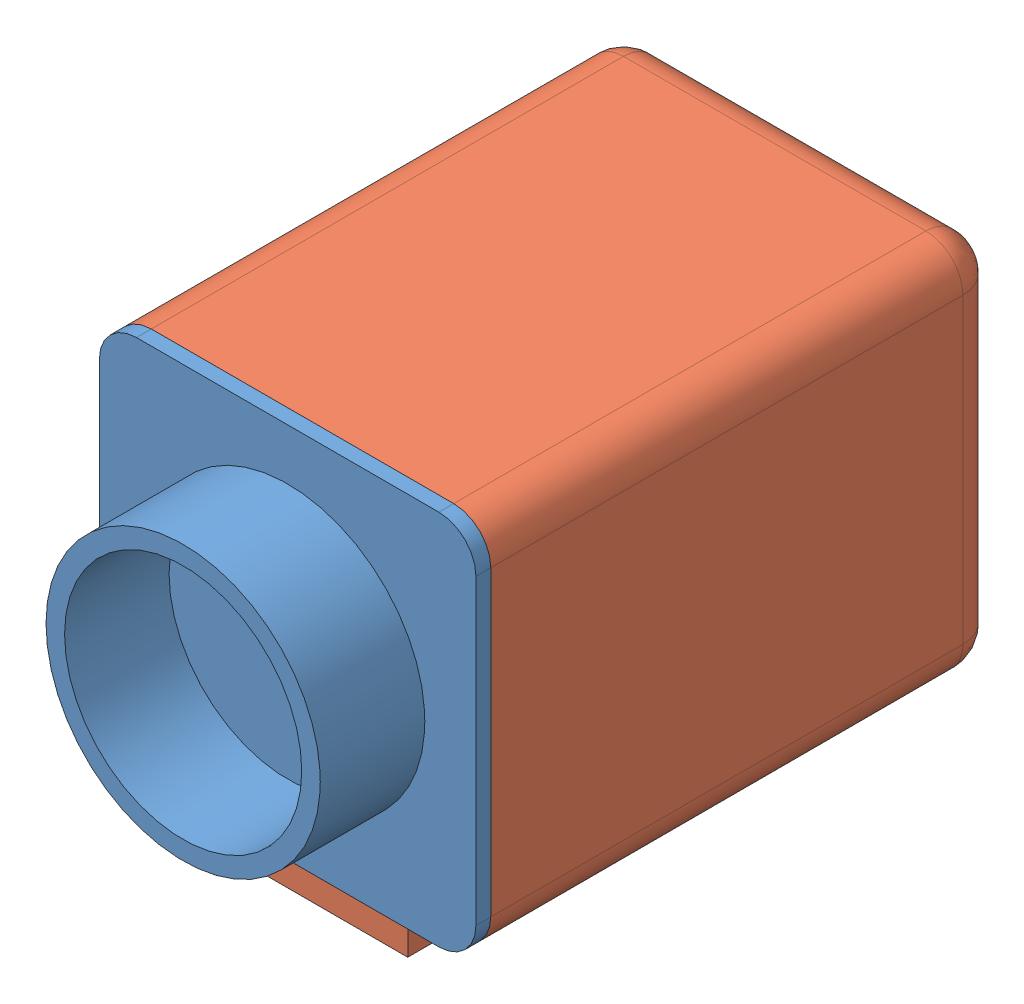
SolidWorks assembly Camara, configuration Default. Lengths in mm.
Overall size (50.8 57.8 84.8).
2 component instances, 2 part files, 3 mates.
Components (placement in the parent):
- Encaixe_lente-1: Encaixe_lente [Default] at (9.935 10.7441 16.5114) size (50.8 50.8 16.1)
- Carapaca-1: Carapaca [Default] at (9.935 10.7441 -17.8386) size (50.8 57.8 68.7)
Mates (geometry in assembly coordinates):
- Coincident1: coincident anti-aligned: plane of Encaixe_lente-1 through (-15.465 -14.6559 16.5114) normal (0 0 -1); plane of Carapaca-1 through (-15.465 36.1441 16.5114) normal (0 0 1)
- Coincident2: coincident anti-aligned: circle of Encaixe_lente-1; circle of Carapaca-1
- Concentric1: concentric aligned: cylinder of Encaixe_lente-1 through (30.335 -9.6559 18.5114) axis (0 0 -1) radius 5; cylinder of Carapaca-1 through (30.335 -9.6559 16.5114) axis (0 0 -1) radius 5
